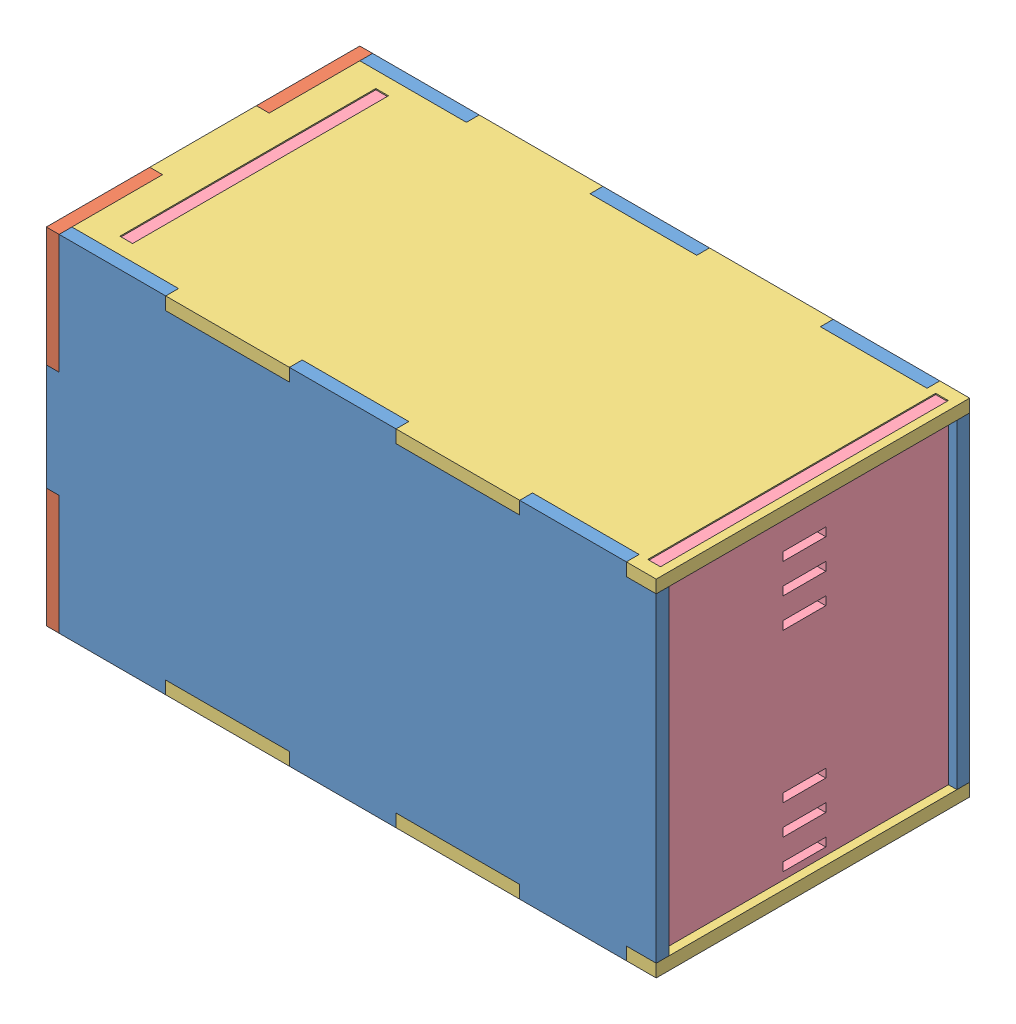
SolidWorks assembly Caja, configuration Predeterminado. Lengths in mm.
Overall size (286 162.55 147).
7 component instances, 4 part files, 22 mates.
Components (placement in the parent):
- Lateral-1: Lateral [Predeterminado] at (-30.5967 143.4521 355.7099) size (286 162 6)
- Lateral-2: Lateral [Predeterminado] at (-30.5967 143.4521 214.7099) size (286 162 6)
- Tapa trasera-1: Tapa trasera [Predeterminado] at (-169.5967 143.4521 288.2099) x (0 0 -1) z (1 0 0) size (147 162 6)
- Superior-3: Superior [Inferior] at (-30.5967 62.4521 288.2099) size (286 6 147)
- Superior-4: Superior [Superior] at (-30.5967 218.4521 288.2099) size (286 6 147)
- TapaDeslizable-1: TapaDeslizable [Frontal] at (106.4283 142.904 288.2099) size (6 162 135)
- TapaDeslizable-2: TapaDeslizable [Interior] at (-148.6217 142.904 282.2099) size (6 162 120)
Mates (geometry in assembly coordinates):
- Coincidente1: coincident: plane of assembly; plane of assembly; plane of Lateral-1 through (102.4033 143.4521 361.7099) normal (1 0 0); plane of Lateral-2 through (102.4033 143.4521 220.7099) normal (1 0 0)
- Coincidente2: coincident: plane of assembly; plane of assembly; plane of Lateral-1 through (-30.5967 224.4521 361.7099) normal (0 1 0); plane of Lateral-2 through (-30.5967 224.4521 220.7099) normal (0 1 0)
- Coincidente15: coincident: plane of assembly; plane of assembly; plane of Lateral-1 through (-30.5967 143.4521 361.7099) normal (0 0 1); plane of Tapa trasera-1 through (-163.5967 143.4521 361.7099) normal (0 0 1)
- Coincidente23: coincident: plane of assembly; plane of assembly; plane of Tapa trasera-1 through (-169.5967 143.4521 288.2099) normal (-1 0 0); plane of Superior-3 through (-169.5967 62.4521 263.2099) normal (-1 0 0)
- Coincidente24: coincident: plane of assembly; plane of assembly; plane of Lateral-2 through (-30.5967 143.4521 220.7099) normal (0 0 1); plane of Superior-3 through (-30.5967 68.4521 220.7099) normal (0 0 -1)
- Coincidente25: coincident: plane of assembly; plane of assembly; plane of Tapa trasera-1 through (-163.5967 68.4521 288.2099) normal (0 -1 0); plane of Superior-3 through (-30.5967 68.4521 288.2099) normal (0 1 0)
- Coincidente26: coincident: plane of assembly; plane of assembly; plane of Lateral-1 through (-30.5967 143.4521 355.7099) normal (0 0 -1); plane of Superior-4 through (-30.5967 224.4521 355.7099) normal (0 0 1)
- Coincidente27: coincident: plane of assembly; plane of assembly; plane of Lateral-1 through (-30.5967 143.4521 355.7099) normal (0 0 -1); plane of Superior-3 through (-30.5967 68.4521 355.7099) normal (0 0 1)
- Coincidente28: coincident: plane of assembly; plane of assembly; plane of Lateral-1 through (-30.5967 68.4521 361.7099) normal (0 -1 0); plane of Superior-3 through (-30.5967 68.4521 288.2099) normal (0 1 0)
- Coincidente30: coincident: line of assembly; line of assembly; line of Lateral-1 through (-163.5967 224.4521 361.7099) axis (0 0 -1); line of Superior-4 through (-163.5967 224.4521 313.2099) axis (0 0 1)
- Coincidente31: coincident: plane of assembly; plane of assembly; plane of Lateral-1 through (-163.5967 143.4521 361.7099) normal (-1 0 0); plane of Tapa trasera-1 through (-163.5967 143.4521 288.2099) normal (1 0 0)
- Paralelo1: parallel: plane of assembly; plane of assembly; plane of Superior-3 through (-30.5967 68.4521 288.2099) normal (0 1 0); plane of Superior-4 through (-30.5967 224.4521 288.2099) normal (0 1 0)
- Ancho1: width: plane of assembly; plane of assembly; plane of assembly; plane of assembly; plane of TapaDeslizable-1 through (112.4283 142.904 288.2099) normal (1 0 0); plane of TapaDeslizable-1 through (106.4283 142.904 288.2099) normal (-1 0 0); plane of Superior-4 through (106.4533 218.4521 220.7099) normal (1 0 0); plane of Superior-4 through (112.4033 218.4521 220.7099) normal (-1 0 0)
- Ancho3: width: plane of assembly; plane of assembly; plane of assembly; plane of assembly; plane of TapaDeslizable-1 through (112.4283 223.904 355.7099) normal (0 0 1); plane of TapaDeslizable-1 through (112.4283 223.904 220.7099) normal (0 0 -1); plane of Lateral-2 through (-30.5967 143.4521 220.7099) normal (0 0 1); plane of Lateral-1 through (-30.5967 143.4521 355.7099) normal (0 0 -1)
- Ancho6: width: plane of assembly; plane of assembly; plane of assembly; plane of assembly; plane of Superior-4 through (-142.6467 218.4521 228.2099) normal (-1 0 0); plane of Superior-4 through (-148.5967 218.4521 228.2099) normal (1 0 0); plane of TapaDeslizable-2 through (-148.6217 142.904 282.2099) normal (-1 0 0); plane of TapaDeslizable-2 through (-142.6217 142.904 282.2099) normal (1 0 0)
- Ancho7: width: plane of assembly; plane of assembly; plane of assembly; plane of assembly; plane of TapaDeslizable-2 through (-142.6217 61.904 228.2099) normal (0 0 -1); plane of TapaDeslizable-2 through (-148.6217 61.904 348.2099) normal (0 0 1); plane of Lateral-2 through (-30.5967 143.4521 214.7099) normal (0 0 -1); plane of Lateral-1 through (-30.5967 143.4521 361.7099) normal (0 0 1)
- Coincidente33: coincident: plane of assembly; plane of assembly; plane of TapaDeslizable-1 through (112.4283 223.904 355.7099) normal (0 1 0); plane of TapaDeslizable-2 through (-142.6217 223.904 349.7099) normal (0 1 0)
- Paralelo2: parallel: plane of assembly; plane of assembly; plane of Lateral-1 through (-30.5967 143.4521 355.7099) normal (0 0 -1); plane of Lateral-2 through (-30.5967 143.4521 220.7099) normal (0 0 1)
- Paralelo3: parallel: plane of assembly; plane of assembly; plane of Superior-3 through (-30.5967 68.4521 288.2099) normal (0 1 0); plane of Superior-4 through (-30.5967 224.4521 288.2099) normal (0 1 0)
- Paralelo4: parallel: plane of assembly; plane of assembly; plane of TapaDeslizable-1 through (106.4283 142.904 288.2099) normal (-1 0 0); plane of TapaDeslizable-2 through (-148.6217 142.904 282.2099) normal (-1 0 0)
- Paralelo5: parallel: plane of assembly; plane of assembly; plane of Lateral-2 through (-30.5967 143.4521 214.7099) normal (0 0 -1); plane of TapaDeslizable-2 through (-142.6217 61.904 228.2099) normal (0 0 -1)
- Paralelo6: parallel: plane of assembly; plane of assembly; plane of Lateral-2 through (-30.5967 143.4521 214.7099) normal (0 0 -1); plane of TapaDeslizable-1 through (112.4283 223.904 220.7099) normal (0 0 -1)
